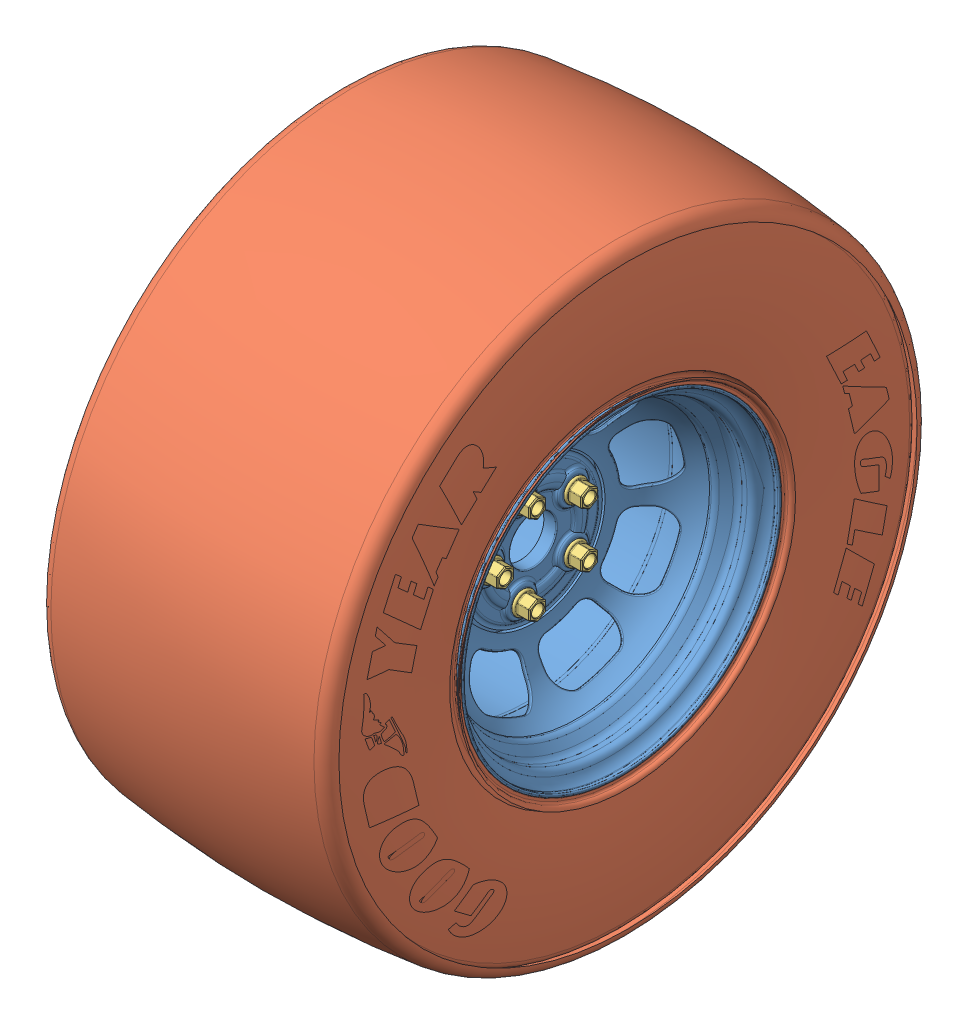
SolidWorks assembly NASCAR Wheel & Tire, configuration Default. Lengths in mm.
Overall size (380.27 799 799).
7 component instances, 3 part files, 0 mates.
Components (placement in the parent):
- NASCAR Aero Wheel (15x14)-1: NASCAR Aero Wheel (15x14) [Default] at (-224.79 0 0) x (0 0.309017 -0.951057) z (1 0 0) size (415.41 415.41 355.6)
- NASCAR 28-10-15 Goodyear Eagle-1: NASCAR 28-10-15 Goodyear Eagle [Default] at (-46.99 0 0) size (380.27 799 799)
- 15mm Lug Nut OPEN-ENDED-1: 15mm Lug Nut OPEN-ENDED [Default] at (16.129 -35.2671 -48.541) size (25 30 30)
- 15mm Lug Nut OPEN-ENDED-2: 15mm Lug Nut OPEN-ENDED [Default] at (16.129 35.2671 -48.541) size (25 30 30)
- 15mm Lug Nut OPEN-ENDED-3: 15mm Lug Nut OPEN-ENDED [Default] at (16.129 57.0634 18.541) size (25 30 30)
- 15mm Lug Nut OPEN-ENDED-4: 15mm Lug Nut OPEN-ENDED [Default] at (16.129 0 60) size (25 30 30)
- 15mm Lug Nut OPEN-ENDED-5: 15mm Lug Nut OPEN-ENDED [Default] at (16.129 -57.0634 18.541) size (25 30 30)
